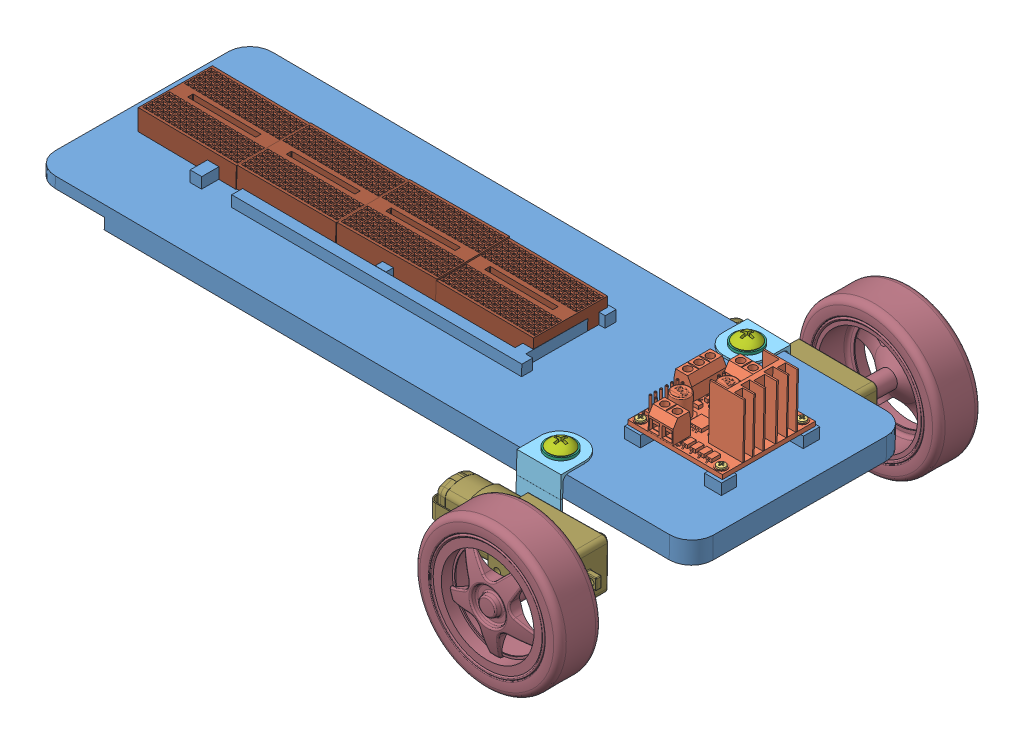
SolidWorks assembly Ensamblaje plataforma, configuration Default. Lengths in mm.
Overall size (300.76 90.33 196.85).
49 component instances, 19 part files, 66 mates.
Components (placement in the parent):
- Assem2^Ensamblaje plataforma-1: Assem2^Ensamblaje plataforma [Default] at (0.789 12.8882 -10.4943) x (0.999913 -0.011798 -0.005953) z (0.006078 0.010581 0.999926) size (300 15 100) (virtual)
  - Plataforma base-1: Plataforma base [Default] at (153.6211 143.2192 210.7445) size (300 15 100)
- L298N Stepper Motor Driver (Red)-Part File_1-1: L298N Stepper Motor Driver (Red)-Part File_1 [Default] at (301.9437 169.6368 181.343) x (0.008999 0.010546 0.999904) z (-0.999891 0.011828 0.008874) size (43 28.01 43)
- binding head screw_ai-7: binding head screw_ai [CR-BHMS 0.073-64x0.5625x0.5625-N] at (283.259 172.8996 162.7318) x (-0.011734 -0.999874 0.010651) z (0.010981 0.010523 0.999884) size (20.07 3.89 3.89)
- binding head screw_ai-8: binding head screw_ai [CR-BHMS 0.073-64x0.5625x0.5625-N] at (283.5953 173.2939 200.1077) x (-0.011734 -0.999874 0.010651) z (0.010981 0.010523 0.999884) size (20.07 3.89 3.89)
- binding head screw_ai-9: binding head screw_ai [CR-BHMS 0.073-64x0.5625x0.5625-N] at (320.3331 172.8593 199.7817) x (-0.011734 -0.999874 0.010651) z (0.010981 0.010523 0.999884) size (20.07 3.89 3.89)
- binding head screw_ai-10: binding head screw_ai [CR-BHMS 0.073-64x0.75x0.75-N] at (319.9967 172.465 162.4057) x (-0.011734 -0.999874 0.010651) z (0.010981 0.010523 0.999884) size (20.07 3.89 3.89)
- machine screw nut hex_ai-2: machine screw nut hex_ai [MSHXNUT 0.073-64-S-N] at (283.5682 170.9827 200.1323) x (0.99987 -0.011614 0.011203) z (-0.011734 -0.999874 0.010651) size (3.96 4.58 1.27)
- machine screw nut hex_ai-4: machine screw nut hex_ai [MSHXNUT 0.073-64-S-N] at (283.3447 151.9351 200.3352) x (0.99987 -0.011614 0.011203) z (-0.011734 -0.999874 0.010651) size (3.96 4.58 1.27)
- machine screw nut hex_ai-5: machine screw nut hex_ai [MSHXNUT 0.073-64-S-N] at (320.6337 153.3501 200.5493) x (0.99987 -0.011614 0.011203) z (-0.011734 -0.999874 0.010651) size (3.96 4.58 1.27)
- machine screw nut hex_ai-6: machine screw nut hex_ai [MSHXNUT 0.073-64-S-N] at (319.9415 167.7542 162.4559) x (0.99987 -0.011614 0.011203) z (-0.011734 -0.999874 0.010651) size (3.96 4.58 1.27)
- machine screw nut hex_ai-7: machine screw nut hex_ai [MSHXNUT 0.073-64-S-N] at (320.5853 152.9447 162.4412) x (0.99987 -0.011614 0.011203) z (-0.011734 -0.999874 0.010651) size (3.96 4.58 1.27)
- machine screw nut hex_ai-8: machine screw nut hex_ai [MSHXNUT 0.073-64-S-N] at (283.0083 151.5409 162.9593) x (0.99987 -0.011614 0.011203) z (-0.011734 -0.999874 0.010651) size (3.96 4.58 1.27)
- L bracket-1: L bracket [fillet] at (261.7617 166.8658 234.9781) x (-0.011734 -0.999874 0.010651) z (0.99985 -0.011868 -0.012638) size (40 20 20)
- L bracket-2: L bracket [fillet] at (281.5806 165.4754 129.2207) x (-0.011734 -0.999874 0.010651) z (-0.999906 0.011657 -0.007263) size (40 20 20)
- flat washer type a selected narrow_ai-3: flat washer type a selected narrow_ai [Selected Narrow FW 0.25] at (271.6351 166.6417 224.8168) x (-0.011734 -0.999874 0.010651) z (-0.01136 0.010785 0.999877) size (1.24 12.7 12.7)
- flat washer type a selected narrow_ai-4: flat washer type a selected narrow_ai [Selected Narrow FW 0.25] at (271.5069 165.6998 139.1835) x (-0.011734 -0.999874 0.010651) z (-0.01136 0.010785 0.999877) size (1.24 12.7 12.7)
- truss head screw_ai-5: truss head screw_ai [CR-THMS 0.19-24x0.75x0.75-N] at (271.6848 170.883 224.7716) x (-0.011734 -0.999874 0.010651) z (-0.01136 0.010785 0.999877) size (22 11.38 11.38)
- truss head screw_ai-6: truss head screw_ai [CR-THMS 0.19-24x0.75x0.75-N] at (271.5567 169.941 139.1383) x (-0.011734 -0.999874 0.010651) z (-0.01136 0.010785 0.999877) size (22 11.38 11.38)
- flat washer type b regular_ai-5: flat washer type b regular_ai [Regular FW 0.086] at (271.0581 131.529 130.5102) x (0.007138 -0.010736 -0.999917) z (0.999909 -0.011365 0.00726) size (0.81 6.35 6.35)
- flat washer type b regular_ai-6: flat washer type b regular_ai [Regular FW 0.086] at (271.2717 149.7347 130.3162) x (0.007138 -0.010736 -0.999917) z (0.999909 -0.011365 0.00726) size (0.81 6.35 6.35)
- flat washer type b wide_ai-3: flat washer type b wide_ai [Wide FW 0.086] at (274.1118 143.1002 233.7268) x (0.008955 0.011258 0.999897) z (-0.999897 -0.011157 0.00908) size (0.81 8.74 8.74)
- flat washer type b wide_ai-4: flat washer type b wide_ai [Wide FW 0.086] at (271.4602 132.657 233.9126) x (0.012763 0.010502 0.999863) z (-0.999855 -0.011115 0.01288) size (0.81 8.74 8.74)
- hex jam nut_ai-2: hex jam nut_ai [HJNUT 0.2500-20-D-N] at (271.4552 151.3169 224.98) x (0.999876 -0.011621 0.010593) z (-0.011734 -0.999874 0.010651) size (11.11 12.83 4.14)
- hex jam nut_ai-3: hex jam nut_ai [HJNUT 0.2500-20-D-N] at (271.3275 150.4061 139.3464) x (0.999876 -0.011621 0.010593) z (-0.011734 -0.999874 0.010651) size (11.11 12.83 4.14)
- MINIPROTOBOARD-1: MINIPROTOBOARD [Default] at (162.3264 166.9533 178.7314) x (0.999748 -0.011935 -0.018989) z (0.019114 0.010426 0.999763) size (45 9.5 34)
- MINIPROTOBOARD-2: MINIPROTOBOARD [Default] at (206.9868 165.7183 178.3164) x (0.999931 -0.011734 0.000073) z (0.000052 0.010652 0.999943) size (45 9.5 34)
- MINIPROTOBOARD-3: MINIPROTOBOARD [Default] at (117.1538 167.1533 179.358) x (0.999893 -0.011825 -0.008593) z (0.008717 0.01055 0.999906) size (45 9.5 34)
- MINIPROTOBOARD-4: MINIPROTOBOARD [Default] at (72.0061 167.3155 179.5543) x (0.999931 -0.011734 0.000073) z (0.000052 0.010652 0.999943) size (45 9.5 34)
- Moto Reductor - Rueda-1: Moto Reductor - Rueda [Predeterminado] at (332.6461 144.5484 56.2291) x (0.999975 0.000031 0.007138) z (-0.007138 0.010736 0.999917) size (86.5 66 53.9)
  - Moto Reductor 01-1: Moto Reductor 01 [Predeterminado] at (-77.2566 -5.0689 64.1747) size (69.7 22.5 36.8)
  - Rueda 01-2: Rueda 01 [Predeterminado] at (-40.4566 -5.0689 48.6747) x (0 0 -1) z (1 0 0) size (25 66 66)
- Moto Reductor - Rueda-2: Moto Reductor - Rueda [Predeterminado] at (333.4674 137.1162 307.96) x (0.999919 -0.000131 -0.012762) z (-0.012763 -0.010502 -0.999863) size (86.5 66 53.9)
  - Moto Reductor 01-1: Moto Reductor 01 [Predeterminado] at (-77.2566 -5.0689 64.1747) size (69.7 22.5 36.8)
  - Rueda 01-2: Rueda 01 [Predeterminado] at (-40.4566 -5.0689 48.6747) x (0 0 -1) z (1 0 0) size (25 66 66)
- Ensamble_Rueda_Loca-2: Ensamble_Rueda_Loca [Predeterminado] at (113.0599 150.7717 140.7008) x (0.988318 -0.001958 -0.152395) z (0.15239 -0.002472 0.988317) size (50.13 42.44 33)
  - Base_rueda_loca-1: Base_rueda_loca [Predeterminado] at (0.7239 4.3377 41.0399) size (41.04 4 33)
  - rueda loca-1: rueda loca [Predeterminado] at (0.7239 -3.6623 41.0399) x (0.15258 0 -0.988291) z (0.988291 0 0.15258) size (23.5 25.74 27.45)
  - Llanta-1: Llanta [Predeterminado] at (12.3641 -17.7732 42.8347) x (0.152548 0.020285 -0.988088) z (0.775985 0.616686 0.132462) size (12.69 24.5 24.5)
  - Eje_planta-1: Eje_planta [Predeterminado] at (10.931 -17.9637 52.1172) x (0.152548 0.020285 -0.988088) z (0.959429 -0.242914 0.143137) size (19.4 6 6)
  - Pasante_Base-1: Pasante_Base [Predeterminado] at (0.7239 4.3377 41.0399) size (7 3 7)
- truss head screw_ai-10: truss head screw_ai [CR-THMS 0.086-64x0.75x0.75-N] at (136.8183 167.8076 170.7554) x (-0.011734 -0.999874 0.010651) z (-0.011356 0.010785 0.999877) size (15.6 4.93 4.93)
- truss head screw_ai-11: truss head screw_ai [CR-THMS 0.086-64x0.75x0.75-N] at (137.0571 168.0669 195.3664) x (-0.011734 -0.999874 0.010651) z (-0.011356 0.010785 0.999877) size (15.6 4.93 4.93)
- truss head screw_ai-12: truss head screw_ai [CR-THMS 0.086-64x0.5625x0.5625-N] at (107.7893 168.4099 195.3243) x (-0.011734 -0.999874 0.010651) z (-0.011356 0.010785 0.999877) size (15.6 4.93 4.93)
- truss head screw_ai-13: truss head screw_ai [CR-THMS 0.086-64x0.75x0.75-N] at (107.6412 168.1521 170.9529) x (-0.011734 -0.999874 0.010651) z (-0.011356 0.010785 0.999877) size (15.6 4.93 4.93)
- hex nut style 1 gradeab_bsi-9: hex nut style 1 gradeab_bsi [BS EN 24032 - M2.5 - W - N] at (107.4343 150.5206 171.1407) x (0.999871 -0.011616 0.011069) z (-0.011734 -0.999874 0.010651) size (5 5.77 2)
- hex nut style 1 gradeab_bsi-10: hex nut style 1 gradeab_bsi [BS EN 24032 - M2.5 - W - N] at (107.5824 150.7785 195.5122) x (0.999871 -0.011616 0.011069) z (-0.011734 -0.999874 0.010651) size (5 5.77 2)
- hex nut style 1 gradeab_bsi-11: hex nut style 1 gradeab_bsi [BS EN 24032 - M2.5 - W - N] at (136.8502 150.4354 195.5542) x (0.999871 -0.011616 0.011069) z (-0.011734 -0.999874 0.010651) size (5 5.77 2)
- hex nut style 1 gradeab_bsi-12: hex nut style 1 gradeab_bsi [BS EN 24032 - M2.5 - W - N] at (136.6114 150.1761 170.9433) x (0.999871 -0.011616 0.011069) z (-0.011734 -0.999874 0.010651) size (5 5.77 2)
Mates (geometry in assembly coordinates):
- Concentric2: concentric: cylinder of assembly; circle of assembly; cylinder of Assem2^Ensamblaje plataforma-1/Plataforma base-1 through (281.9889 64.6718 163.8847) axis (0.011734 0.999874 -0.010651) radius 1.8; circle of L298N Stepper Motor Driver (Red)-Part File_1-1
- Concentric7: concentric: cylinder of assembly; cylinder of assembly; cylinder of L298N Stepper Motor Driver (Red)-Part File_1-1 through (283.2186 169.4587 162.7685) axis (0.011734 0.999874 -0.010651) radius 1.75; cylinder of binding head screw_ai-7 through (283.557 198.2965 162.4613) axis (0.011734 0.999874 -0.010651) radius 0.9271
- Coincident22: coincident: plane of assembly; plane of assembly; plane of L298N Stepper Motor Driver (Red)-Part File_1-1 through (285.7537 171.8018 160.1907) normal (0.011734 0.999874 -0.010651); plane of binding head screw_ai-7 through (284.1737 171.8474 162.7328) normal (-0.011734 -0.999874 0.010651)
- Concentric8: concentric: cylinder of assembly; cylinder of assembly; cylinder of L298N Stepper Motor Driver (Red)-Part File_1-1 through (283.555 169.8529 200.1444) axis (0.011734 0.999874 -0.010651) radius 1.75; cylinder of binding head screw_ai-8 through (283.8934 198.6907 199.8372) axis (0.011734 0.999874 -0.010651) radius 0.9271
- Coincident23: coincident: plane of assembly; plane of assembly; plane of L298N Stepper Motor Driver (Red)-Part File_1-1 through (286.0901 172.196 197.5666) normal (0.011734 0.999874 -0.010651); plane of binding head screw_ai-8 through (284.5101 172.2416 200.1087) normal (-0.011734 -0.999874 0.010651)
- Concentric9: concentric: cylinder of assembly; cylinder of assembly; cylinder of L298N Stepper Motor Driver (Red)-Part File_1-1 through (320.2927 169.4183 199.8183) axis (0.011734 0.999874 -0.010651) radius 1.75; cylinder of binding head screw_ai-9 through (320.6312 198.2561 199.5111) axis (0.011734 0.999874 -0.010651) radius 0.9271
- Coincident24: coincident: plane of assembly; plane of assembly; plane of L298N Stepper Motor Driver (Red)-Part File_1-1 through (322.8279 171.7614 197.2405) normal (0.011734 0.999874 -0.010651); plane of binding head screw_ai-9 through (321.2479 171.807 199.7827) normal (-0.011734 -0.999874 0.010651)
- Concentric10: concentric: cylinder of assembly; cylinder of assembly; cylinder of L298N Stepper Motor Driver (Red)-Part File_1-1 through (319.9564 169.0241 162.4424) axis (0.011734 0.999874 -0.010651) radius 1.75; cylinder of binding head screw_ai-10 through (320.2948 197.8619 162.1352) axis (0.011734 0.999874 -0.010651) radius 0.9271
- Coincident25: coincident: plane of assembly; plane of assembly; plane of L298N Stepper Motor Driver (Red)-Part File_1-1 through (322.4915 171.3672 159.8646) normal (0.011734 0.999874 -0.010651); plane of binding head screw_ai-10 through (320.9115 171.4128 162.4068) normal (-0.011734 -0.999874 0.010651)
- Concentric111: concentric: cone of assembly; cylinder of assembly; cone of binding head screw_ai-8 through (283.5831 172.2526 200.1188) axis (0.011734 0.999874 -0.010651); cylinder of machine screw nut hex_ai-2 through (283.862 196.0171 199.8656) axis (-0.011734 -0.999874 0.010651) radius 0.9271
- Coincident261: coincident: plane of assembly; plane of assembly; plane of binding head screw_ai-8 through (284.5101 172.2416 200.1087) normal (-0.011734 -0.999874 0.010651); plane of machine screw nut hex_ai-2 through (283.5578 172.2772 202.4062) normal (0.011734 0.999874 -0.010651)
- Concentric12: concentric: cylinder of assembly; cylinder of assembly; cylinder of L298N Stepper Motor Driver (Red)-Part File_1-1 through (283.555 169.8529 200.1444) axis (0.011734 0.999874 -0.010651) radius 1.75; cylinder of machine screw nut hex_ai-4 through (283.6385 176.9695 200.0686) axis (-0.011734 -0.999874 0.010651) radius 0.9271
- Coincident27: coincident: plane of assembly; plane of assembly; plane of binding head screw_ai-8 through (284.2866 153.194 200.3116) normal (-0.011734 -0.999874 0.010651); plane of machine screw nut hex_ai-4 through (283.3342 153.2296 202.6091) normal (0.011734 0.999874 -0.010651)
- Concentric13: concentric: cylinder of assembly; cylinder of assembly; cylinder of Assem2^Ensamblaje plataforma-1/Plataforma base-1 through (319.5926 64.6312 201.4944) axis (0.011734 0.999874 -0.010651) radius 1.8; cylinder of machine screw nut hex_ai-5 through (320.9275 178.3844 200.2826) axis (-0.011734 -0.999874 0.010651) radius 0.9271
- Coincident28: coincident: plane of assembly; plane of assembly; plane of Assem2^Ensamblaje plataforma-1/Plataforma base-1 through (157.3582 156.5069 197.7945) normal (-0.011734 -0.999874 0.010651); plane of machine screw nut hex_ai-5 through (320.6233 154.6446 202.8232) normal (0.011734 0.999874 -0.010651)
- Concentric14: concentric: cylinder of assembly; cylinder of assembly; cylinder of binding head screw_ai-10 through (320.2948 197.8619 162.1352) axis (0.011734 0.999874 -0.010651) radius 0.9271; cylinder of machine screw nut hex_ai-6 through (320.2352 192.7886 162.1892) axis (-0.011734 -0.999874 0.010651) radius 0.9271
- Coincident29: coincident: plane of assembly; plane of assembly; plane of L298N Stepper Motor Driver (Red)-Part File_1-1 through (317.4039 169.0273 159.9351) normal (-0.011734 -0.999874 0.010651); plane of machine screw nut hex_ai-6 through (319.931 169.0487 164.7298) normal (0.011734 0.999874 -0.010651)
- Concentric15: concentric: cylinder of assembly; cylinder of assembly; cylinder of Assem2^Ensamblaje plataforma-1/Plataforma base-1 through (319.5441 64.2258 163.3863) axis (0.011734 0.999874 -0.010651) radius 1.8; cylinder of machine screw nut hex_ai-7 through (320.8791 177.979 162.1745) axis (-0.011734 -0.999874 0.010651) radius 0.9271
- Coincident30: coincident: plane of assembly; plane of assembly; plane of Assem2^Ensamblaje plataforma-1/Plataforma base-1 through (157.3582 156.5069 197.7945) normal (-0.011734 -0.999874 0.010651); plane of machine screw nut hex_ai-7 through (320.5748 154.2392 164.7151) normal (0.011734 0.999874 -0.010651)
- Concentric16: concentric: cylinder of assembly; cylinder of assembly; cylinder of L298N Stepper Motor Driver (Red)-Part File_1-1 through (283.2186 169.4587 162.7685) axis (0.011734 0.999874 -0.010651) radius 1.75; cylinder of machine screw nut hex_ai-8 through (283.3021 176.5753 162.6926) axis (-0.011734 -0.999874 0.010651) radius 0.9271
- Coincident31: coincident: plane of assembly; plane of assembly; plane of binding head screw_ai-7 through (283.9502 152.7998 162.9357) normal (-0.011734 -0.999874 0.010651); plane of machine screw nut hex_ai-8 through (282.9979 152.8354 165.2332) normal (0.011734 0.999874 -0.010651)
- Concentric21: concentric: circle of assembly; circle of assembly; circle of Assem2^Ensamblaje plataforma-1/Plataforma base-1; circle of L bracket-1
- Coincident37: coincident: plane of assembly; line of assembly; plane of Assem2^Ensamblaje plataforma-1/Plataforma base-1 through (157.5342 171.5051 197.6347) normal (0.011734 0.999874 -0.010651); line of L298N Stepper Motor Driver (Red)-Part File_1-1 through (323.6348 169.6093 202.6502) axis (-0.999891 0.011828 0.008874)
- Concentric25: concentric: cylinder of assembly; circle of assembly; cylinder of Assem2^Ensamblaje plataforma-1/Plataforma base-1 through (271.1414 134.5483 139.5153) axis (0.011734 0.999874 -0.010651) radius 5.0077; circle of L bracket-2
- Coincident42: coincident: plane of assembly; line of assembly; plane of Assem2^Ensamblaje plataforma-1/Plataforma base-1 through (157.5342 171.5051 197.6347) normal (0.011734 0.999874 -0.010651); line of L298N Stepper Motor Driver (Red)-Part File_1-1 through (323.6348 169.6093 202.6502) axis (-0.999891 0.011828 0.008874)
- Concentric281: concentric: cylinder of assembly; cylinder of assembly; cylinder of L bracket-1 through (271.5177 156.643 224.9233) axis (0.011734 0.999874 -0.010651) radius 5.0147; cylinder of flat washer type a selected narrow_ai-3 through (272.0449 201.5623 224.4448) axis (0.011734 0.999874 -0.010651) radius 3.175
- Coincident461: coincident: plane of assembly; plane of assembly; plane of L bracket-1 through (281.7587 166.6285 234.7253) normal (0.011734 0.999874 -0.010651); plane of flat washer type a selected narrow_ai-3 through (274.8096 166.6049 224.8532) normal (-0.011734 -0.999874 0.010651)
- Concentric29: concentric: cylinder of assembly; cylinder of assembly; cylinder of L bracket-2 through (271.3896 155.701 139.29) axis (0.011734 0.999874 -0.010651) radius 5.0147; cylinder of flat washer type a selected narrow_ai-4 through (271.9167 200.6204 138.8115) axis (0.011734 0.999874 -0.010651) radius 3.175
- Coincident47: coincident: plane of assembly; plane of assembly; plane of L bracket-2 through (261.5824 165.7086 129.0755) normal (0.011734 0.999874 -0.010651); plane of flat washer type a selected narrow_ai-4 through (274.6815 165.6629 139.22) normal (-0.011734 -0.999874 0.010651)
- Concentric31: concentric: cylinder of assembly; cylinder of assembly; cylinder of L bracket-1 through (271.5177 156.643 224.9233) axis (0.011734 0.999874 -0.010651) radius 5.0147; cylinder of truss head screw_ai-5 through (271.9829 196.2798 224.501) axis (0.011734 0.999874 -0.010651) radius 5.6896
- Coincident48: coincident: plane of assembly; plane of assembly; plane of flat washer type a selected narrow_ai-3 through (277.9988 167.8124 224.8764) normal (0.011734 0.999874 -0.010651); plane of truss head screw_ai-5 through (274.0623 167.8581 224.8312) normal (-0.011734 -0.999874 0.010651)
- Concentric32: concentric: cylinder of assembly; cylinder of assembly; cylinder of L bracket-2 through (271.3896 155.701 139.29) axis (0.011734 0.999874 -0.010651) radius 5.0147; cylinder of truss head screw_ai-6 through (271.8548 195.3378 138.8678) axis (0.011734 0.999874 -0.010651) radius 5.6896
- Coincident49: coincident: plane of assembly; plane of assembly; plane of flat washer type a selected narrow_ai-4 through (277.8707 166.8705 139.2432) normal (0.011734 0.999874 -0.010651); plane of truss head screw_ai-6 through (273.9342 166.9162 139.198) normal (-0.011734 -0.999874 0.010651)
- Concentric38: concentric: cylinder of assembly; cylinder of assembly; cylinder of L bracket-2 through (271.2722 131.2069 100.5127) axis (-0.007138 0.010736 0.999917) radius 1.5; cylinder of flat washer type b regular_ai-5 through (270.8088 131.9039 165.4323) axis (-0.007138 0.010736 0.999917) radius 1.1938
- Coincident55: coincident: plane of assembly; plane of assembly; plane of L bracket-2 through (261.5636 164.7194 130.086) normal (-0.007138 0.010736 0.999917); plane of flat washer type b regular_ai-5 through (271.0717 132.7226 130.4974) normal (0.007138 -0.010736 -0.999917)
- Concentric39: concentric: cylinder of assembly; cylinder of assembly; cylinder of L bracket-2 through (271.3431 149.6273 120.3171) axis (-0.007138 0.010736 0.999917) radius 1.5; cylinder of flat washer type b regular_ai-6 through (271.0224 150.1096 165.2383) axis (-0.007138 0.010736 0.999917) radius 1.1938
- Coincident56: coincident: plane of assembly; plane of assembly; plane of L bracket-2 through (261.5636 164.7194 130.086) normal (-0.007138 0.010736 0.999917); plane of flat washer type b regular_ai-6 through (271.2854 150.9283 130.3035) normal (0.007138 -0.010736 -0.999917)
- Concentric49: concentric: cylinder of assembly; cylinder of assembly; cylinder of Assem2^Ensamblaje plataforma-1/Plataforma base-1 through (271.2691 135.4591 225.149) axis (0.011734 0.999874 -0.010651) radius 5.0077; cylinder of hex jam nut_ai-2 through (271.749 176.3512 224.7133) axis (-0.011734 -0.999874 0.010651) radius 3.175
- Coincident66: coincident: plane of assembly; plane of assembly; plane of Assem2^Ensamblaje plataforma-1/Plataforma base-1 through (157.3582 156.5069 197.7945) normal (-0.011734 -0.999874 0.010651); plane of hex jam nut_ai-2 through (260.3927 155.5857 224.8182) normal (0.011734 0.999874 -0.010651)
- Concentric50: concentric: cylinder of assembly; cylinder of assembly; cylinder of Assem2^Ensamblaje plataforma-1/Plataforma base-1 through (271.1414 134.5483 139.5153) axis (0.011734 0.999874 -0.010651) radius 5.0077; cylinder of hex jam nut_ai-3 through (271.6213 175.4405 139.0797) axis (-0.011734 -0.999874 0.010651) radius 3.175
- Coincident67: coincident: plane of assembly; plane of assembly; plane of Assem2^Ensamblaje plataforma-1/Plataforma base-1 through (157.3582 156.5069 197.7945) normal (-0.011734 -0.999874 0.010651); plane of hex jam nut_ai-3 through (260.2649 154.6749 139.1846) normal (0.011734 0.999874 -0.010651)
- Coincident462: coincident: line of assembly; line of assembly; line of MINIPROTOBOARD-1 through (184.6073 176.0064 161.207) axis (-0.011734 -0.999874 0.010651); line of MINIPROTOBOARD-2 through (184.599 175.3 161.2145) axis (-0.011734 -0.999874 0.010651)
- Coincident463: coincident: line of assembly; line of assembly; line of MINIPROTOBOARD-1 through (139.6186 176.5434 162.0615) axis (-0.011734 -0.999874 0.010651); line of MINIPROTOBOARD-3 through (139.6146 176.2066 162.0651) axis (-0.011734 -0.999874 0.010651)
- Coincident464: coincident: line of assembly; line of assembly; line of MINIPROTOBOARD-3 through (94.6194 176.7388 162.4517) axis (-0.011734 -0.999874 0.010651); line of MINIPROTOBOARD-4 through (94.6151 176.3692 162.4557) axis (-0.011734 -0.999874 0.010651)
- Coincident468: coincident: plane of assembly; plane of assembly; plane of Assem2^Ensamblaje plataforma-1/Plataforma base-1 through (157.4755 166.5057 197.688) normal (0.011734 0.999874 -0.010651); plane of MINIPROTOBOARD-2 through (206.9868 165.7183 178.3164) normal (-0.011734 -0.999874 0.010651)
- Coincident471: coincident: plane of assembly; plane of assembly; plane of Assem2^Ensamblaje plataforma-1/Plataforma base-1 through (157.4755 166.5057 197.688) normal (0.011734 0.999874 -0.010651); plane of MINIPROTOBOARD-4 through (72.0061 167.3155 179.5543) normal (-0.011734 -0.999874 0.010651)
- Concentric282: concentric: circle of assembly; circle of assembly; circle of L bracket-1; circle of flat washer type b wide_ai-4
- Coincident473: coincident: circle of assembly; circle of assembly; circle of L bracket-2; circle of Moto Reductor - Rueda-1/Moto Reductor 01-1
- Coincident474: coincident: circle of assembly; circle of assembly; circle of L bracket-1; circle of Moto Reductor - Rueda-2/Moto Reductor 01-1
- Tangent1: tangent: curve of Assem2^Ensamblaje plataforma-1/Plataforma base-1; edge_curve of ?
- Concentric285: concentric: cylinder of assembly; cylinder of assembly; cylinder of Assem2^Ensamblaje plataforma-1/Plataforma base-1 through (136.2158 116.4678 171.3024) axis (0.011734 0.999874 -0.010651) radius 2.25; cylinder of truss head screw_ai-10 through (137.1163 193.2044 170.4849) axis (0.011734 0.999874 -0.010651) radius 2.4638
- Coincident476: coincident: plane of Assem2^Ensamblaje plataforma-1/Plataforma base-1 through (157.4755 166.5057 197.688) normal (0.011734 0.999874 -0.010651); plane of truss head screw_ai-10 through (137.8946 166.4488 170.7823) normal (-0.011734 -0.999874 0.010651)
- Concentric286: concentric: cylinder of assembly; cylinder of assembly; cylinder of Assem2^Ensamblaje plataforma-1/Plataforma base-1 through (136.9239 156.7222 195.4872) axis (0.011734 0.999874 -0.010651) radius 2.25; cylinder of truss head screw_ai-11 through (137.3551 193.4637 195.0958) axis (0.011734 0.999874 -0.010651) radius 2.4638
- Coincident477: coincident: plane of Assem2^Ensamblaje plataforma-1/Plataforma base-1 through (157.4755 166.5057 197.688) normal (0.011734 0.999874 -0.010651); plane of truss head screw_ai-11 through (138.1333 166.7082 195.3933) normal (-0.011734 -0.999874 0.010651)
- Concentric287: concentric: cylinder of assembly; cylinder of assembly; cylinder of Assem2^Ensamblaje plataforma-1/Plataforma base-1 through (107.1869 117.0702 195.8712) axis (0.011734 0.999874 -0.010651) radius 2.25; cylinder of truss head screw_ai-12 through (108.0874 193.8068 195.0538) axis (0.011734 0.999874 -0.010651) radius 2.4638
- Coincident478: coincident: plane of Assem2^Ensamblaje plataforma-1/Plataforma base-1 through (157.4755 166.5057 197.688) normal (0.011734 0.999874 -0.010651); plane of truss head screw_ai-12 through (108.8656 167.0512 195.3512) normal (-0.011734 -0.999874 0.010651)
- Concentric288: concentric: cylinder of assembly; cylinder of assembly; cylinder of Assem2^Ensamblaje plataforma-1/Plataforma base-1 through (107.0387 116.8123 171.4998) axis (0.011734 0.999874 -0.010651) radius 2.25; cylinder of truss head screw_ai-13 through (107.9392 193.5489 170.6823) axis (0.011734 0.999874 -0.010651) radius 2.4638
- Coincident479: coincident: plane of Assem2^Ensamblaje plataforma-1/Plataforma base-1 through (157.4755 166.5057 197.688) normal (0.011734 0.999874 -0.010651); plane of truss head screw_ai-13 through (108.7175 166.7933 170.9797) normal (-0.011734 -0.999874 0.010651)
- Concentric293: concentric: cylinder of truss head screw_ai-13 through (107.9392 193.5489 170.6823) axis (0.011734 0.999874 -0.010651) radius 1.0922; cylinder of hex nut style 1 gradeab_bsi-9 through (107.7281 175.5549 170.874) axis (-0.011734 -0.999874 0.010651) radius 1.25
- Coincident486: coincident: plane of truss head screw_ai-13 through (108.5498 152.5076 171.1319) normal (-0.011734 -0.999874 0.010651); plane of hex nut style 1 gradeab_bsi-9 through (107.4262 152.5514 174.0058) normal (0.011734 0.999874 -0.010651)
- Concentric294: concentric: cylinder of truss head screw_ai-12 through (108.0874 193.8068 195.0538) axis (0.011734 0.999874 -0.010651) radius 1.0922; cylinder of hex nut style 1 gradeab_bsi-10 through (107.8762 175.8128 195.2455) axis (-0.011734 -0.999874 0.010651) radius 1.25
- Coincident487: coincident: plane of truss head screw_ai-12 through (108.698 152.7655 195.5034) normal (-0.011734 -0.999874 0.010651); plane of hex nut style 1 gradeab_bsi-10 through (107.5743 152.8093 198.3773) normal (0.011734 0.999874 -0.010651)
- Concentric295: concentric: cylinder of truss head screw_ai-11 through (137.3551 193.4637 195.0958) axis (0.011734 0.999874 -0.010651) radius 1.0922; cylinder of hex nut style 1 gradeab_bsi-11 through (137.144 175.4698 195.2875) axis (-0.011734 -0.999874 0.010651) radius 1.25
- Coincident488: coincident: plane of truss head screw_ai-11 through (137.9657 152.4225 195.5454) normal (-0.011734 -0.999874 0.010651); plane of hex nut style 1 gradeab_bsi-11 through (136.842 152.4663 198.4193) normal (0.011734 0.999874 -0.010651)
- Concentric296: concentric: cylinder of truss head screw_ai-10 through (137.1163 193.2044 170.4849) axis (0.011734 0.999874 -0.010651) radius 1.0922; cylinder of hex nut style 1 gradeab_bsi-12 through (136.9052 175.2104 170.6766) axis (-0.011734 -0.999874 0.010651) radius 1.25
- Coincident489: coincident: plane of truss head screw_ai-10 through (137.7269 152.1631 170.9345) normal (-0.011734 -0.999874 0.010651); plane of hex nut style 1 gradeab_bsi-12 through (136.6033 152.2069 173.8084) normal (0.011734 0.999874 -0.010651)
